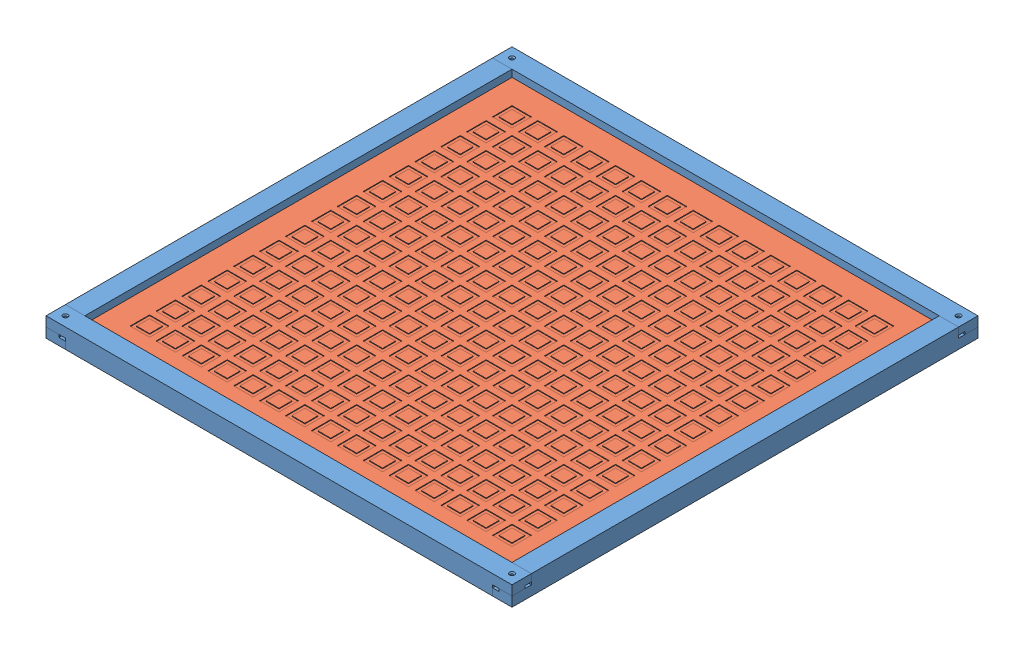
SolidWorks assembly hpgh-002, configuration Default. Lengths in mm.
Overall size (914.4 38.1 914.4).
5 component instances, 2 part files, 15 mates.
Components (placement in the parent):
- 2x2x36-1: 2x2x36 [Default] at origin size (38.1 38.1 914.4)
- 2x2x36-2: 2x2x36 [Default] at (0 38.1 0) x (0 0 -1) z (-1 0 0) size (38.1 38.1 914.4)
- 2x2x36-3: 2x2x36 [Default] at (914.4 38.1 -914.4) x (0 0 1) z (1 0 0) size (38.1 38.1 914.4)
- 2x2x36-4: 2x2x36 [Default] at (914.4 0 -914.4) x (-1 0 0) z (0 0 -1) size (38.1 38.1 914.4)
- hpgh-top1-1: hpgh-top1 [Default] at (457.2 17.4625 -457.2) size (857.25 6.35 857.25)
Mates (geometry in assembly coordinates):
- Coincident1: coincident anti-aligned: plane of 2x2x36-1 through (38.1 19.05 0) normal (0 1 0); plane of 2x2x36-2 through (0 19.05 -38.1) normal (0 -1 0)
- Coincident3: coincident aligned: plane of 2x2x36-1 through (0 0 0) normal (-1 0 0); plane of 2x2x36-2 through (0 0 -38.1) normal (-1 0 0)
- Coincident6: coincident aligned: plane of 2x2x36-1 through (38.1 38.1 0) normal (0 0 1); plane of 2x2x36-2 through (0 38.1 0) normal (0 0 1)
- Coincident7: coincident aligned: plane of 2x2x36-2 through (0 38.1 0) normal (0 0 1); plane of 2x2x36-4 through (876.3 0 0) normal (0 0 1)
- Coincident8: coincident aligned: plane of 2x2x36-2 through (0 38.1 -38.1) normal (0 1 0); plane of 2x2x36-4 through (876.3 38.1 -914.4) normal (0 1 0)
- Coincident9: coincident aligned: plane of 2x2x36-2 through (914.4 38.1 -38.1) normal (1 0 0); plane of 2x2x36-4 through (914.4 0 -914.4) normal (1 0 0)
- Coincident13: coincident aligned: plane of 2x2x36-1 through (38.1 0 -914.4) normal (0 0 -1); plane of 2x2x36-3 through (914.4 38.1 -914.4) normal (0 0 -1)
- Coincident14: coincident aligned: plane of 2x2x36-1 through (0 0 0) normal (-1 0 0); plane of 2x2x36-3 through (0 38.1 -876.3) normal (-1 0 0)
- Coincident15: coincident aligned: plane of 2x2x36-1 through (38.1 38.1 0) normal (0 1 0); plane of 2x2x36-3 through (914.4 38.1 -876.3) normal (0 1 0)
- Coincident16: coincident anti-aligned: plane of ? through (457.2 20.6375 -457.2) normal (0 -1 0); plane of hpgh-top1-1 through (457.2 20.6375 -457.2) normal (0 1 0)
- Coincident17: coincident aligned: plane of ? through (885.825 23.8125 -885.825) normal (1 0 0); plane of hpgh-top1-1 through (885.825 20.6375 -885.825) normal (1 0 0)
- Coincident18: coincident aligned: plane of ? through (885.825 23.8125 -885.825) normal (0 0 -1); plane of hpgh-top1-1 through (885.825 20.6375 -885.825) normal (0 0 -1)
- Width1: width aligned: plane of 2x2x36-2 through (914.4 13.97 -38.1) normal (0 1 0); plane of 2x2x36-2 through (914.4 24.13 -38.1) normal (0 -1 0); plane of ? through (457.2 23.8125 -457.2) normal (0 1 0); plane of hpgh-top1-1 through (457.2 14.2875 -457.2) normal (0 -1 0)
- Width2: width aligned: plane of 2x2x36-2 through (914.4 13.97 -25.4) normal (0 0 -1); plane of 2x2x36-3 through (0 13.97 -889) normal (0 0 1); plane of hpgh-top1-1 through (885.825 20.6375 -885.825) normal (0 0 -1); plane of hpgh-top1-1 through (885.825 20.6375 -28.575) normal (0 0 1)
- Width3: width aligned: plane of 2x2x36-1 through (25.4 24.13 -914.4) normal (1 0 0); plane of 2x2x36-4 through (889 24.13 0) normal (-1 0 0); plane of hpgh-top1-1 through (885.825 20.6375 -885.825) normal (1 0 0); plane of hpgh-top1-1 through (28.575 20.6375 -885.825) normal (-1 0 0)
